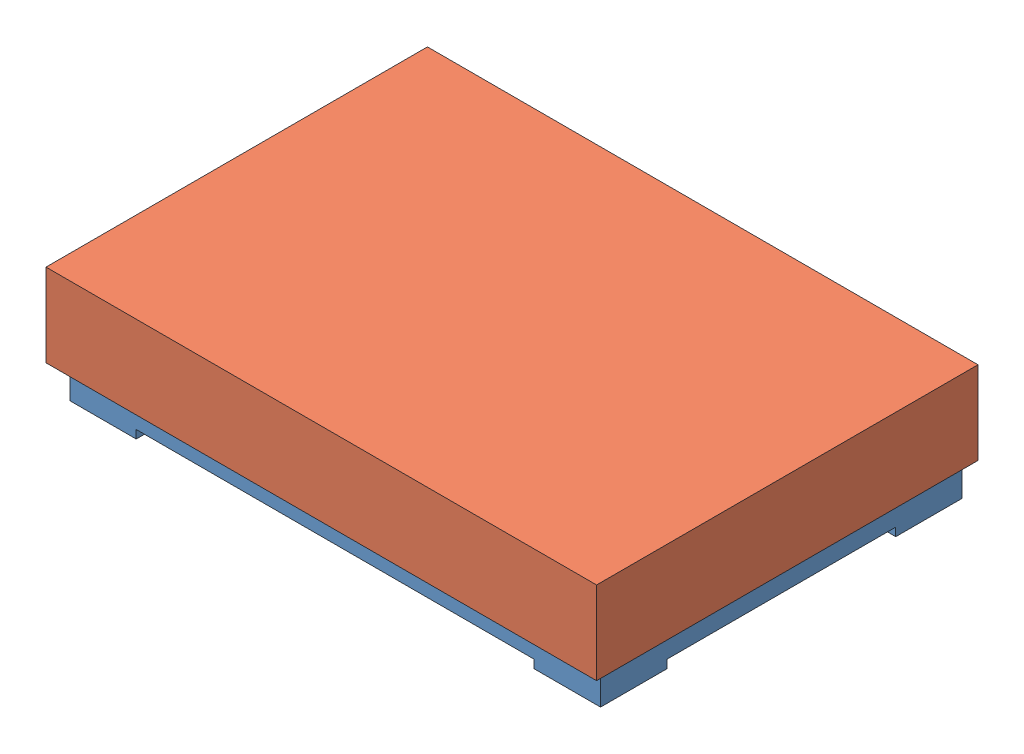
SolidWorks assembly Box_Assembly, configuration Default. Lengths in mm.
Overall size (210.82 44.32 146.05).
2 component instances, 2 part files, 3 mates.
Components (placement in the parent):
- Box_For_Electronics-1: Box_For_Electronics [Default] at origin size (203.2 41.27 138.43)
- Lid_for_box-1: Lid_for_box [Default] at (-0.762 9.398 0.762) size (210.82 31.75 146.05)
Mates (geometry in assembly coordinates):
- Coincident1: coincident anti-aligned: plane of Box_For_Electronics-1 through (0 38.1 0) normal (0 1 0); plane of Lid_for_box-1 through (-0.762 38.1 0.762) normal (0 -1 0)
- Coincident2: coincident anti-aligned: plane of Box_For_Electronics-1 through (-101.6 38.1 -69.215) normal (0 0 -1); plane of Lid_for_box-1 through (-106.172 41.148 -69.215) normal (0 0 1)
- Coincident3: coincident anti-aligned: plane of Box_For_Electronics-1 through (101.6 38.1 69.215) normal (1 0 0); plane of Lid_for_box-1 through (101.6 41.148 73.787) normal (-1 0 0)
